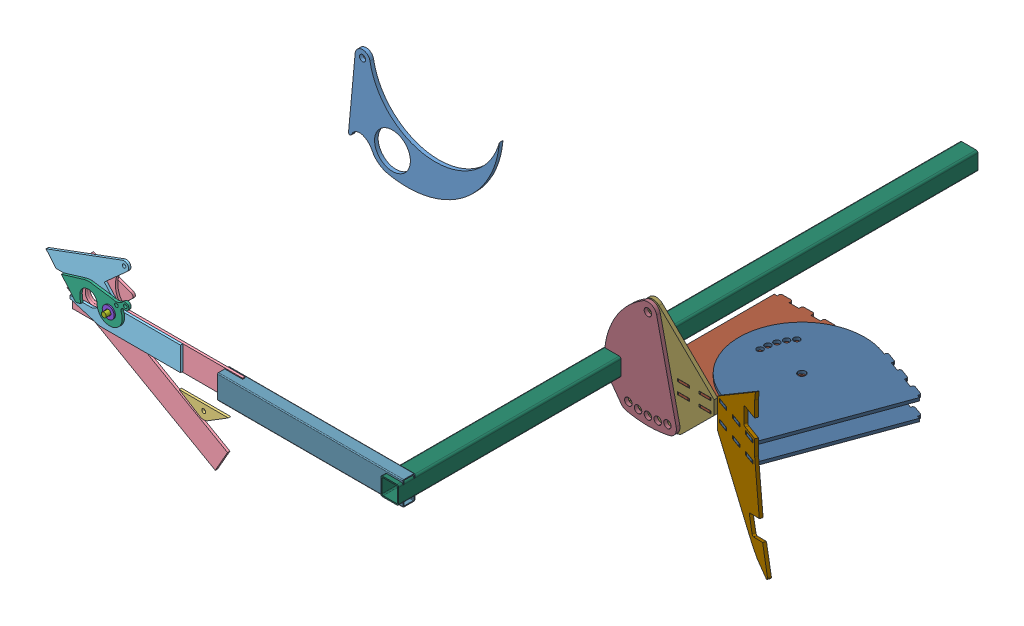
SolidWorks assembly Механизм подъема, configuration 00. Lengths in mm.
Overall size (2305.02 393.93 1176.2).
125 component instances, 32 part files, 102 mates.
Components (placement in the parent):
- Вилка-1: Вилка [--] at (-100 153.8415 0) size (225.09 67 8) (hidden)
- Собачка-1: Собачка [--] at (-64.5 153.8415 -8) size (115.18 50.5 4) (hidden)
- ТП.016.03.05.01 - Ложемент бок (4мм)-1: ТП.016.03.05.01 - Ложемент бок (4мм) [--] at (-100 153.8415 -12) size (285 93.38 4) (hidden)
- ТП.016.03.05.02 - Ложемент низ (4мм)-1: ТП.016.03.05.02 - Ложемент низ (4мм) [--] at (150 118.8415 -16) size (285 4 44) (hidden)
- ТП.016.03.06.01 - Труба связка-1: ТП.016.03.06.01 - Труба связка [--] at (-100 114.8415 28) size (21.3 21.3 971.2) (hidden)
- Модель подъема-1: Модель подъема [--] at (-100 178.8415 -441.6) size (479.74 429.14 0) (hidden)
- ТП.016.03.01.01 - Зуб подъемника (6мм)-1: ТП.016.03.01.01 - Зуб подъемника (6мм) [--] at (-45 169.6674 -441.6) x (0.869959 0.493123 0) z (0 0 1) size (274.94 199.54 6)
- Подшипник ГОСТ 8338-75 -2: Подшипник ГОСТ 8338-75  [Подшипник 205 ГОСТ 8338-75] at (-45 169.6674 -449.1) x (0 0 1) z (-0.017314 -0.99985 0) size (15 52 52) (hidden)
- ТП.016.03.01.02 - Ступица подъема-1: ТП.016.03.01.02 - Ступица подъема [--] at (-45 169.6674 -461.6) x (-1 0 0) z (0 0 -1) size (60 60 40) (hidden)
- ТП.016.03.02 - Ось подъема-1: ТП.016.03.02 - Ось подъема [--] at (-45 169.6674 -461.6) x (-1 0 0) z (0 0 -1) size (25 25 86) (hidden)
- ТП.016.03.03 - Стакан оси подъема-1: ТП.016.03.03 - Стакан оси подъема [--] at (-45 169.6674 -441.6) size (40 40 28) (hidden)
- ТП.016.03.03 - Стакан оси подъема-2: ТП.016.03.03 - Стакан оси подъема [--] at (-45 169.6674 -481.6) x (-1 0 0) z (0 0 -1) size (40 40 28) (hidden)
- ТП.016.03.01.01 - Зуб подъемника (6мм)-2: ТП.016.03.01.01 - Зуб подъемника (6мм) [--] at (-45 169.6674 -475.6) x (0.869959 0.493123 0) z (0 0 1) size (274.94 199.54 6) (hidden)
- Подшипник ГОСТ 8338-75 -3: Подшипник ГОСТ 8338-75  [Подшипник 205 ГОСТ 8338-75] at (-45 169.6674 -474.1) x (0 0 -1) z (0.017314 0.99985 0) size (15 52 52) (hidden)
- ТП.016.03.05.03 - Хомут связки (4мм)-1: ТП.016.03.05.03 - Хомут связки (4мм) [--] at (150 114.8415 -16) size (82.5 38.3 4)
- ТП.016.03.05.04 - Шайба связки (4мм)-1: ТП.016.03.05.04 - Шайба связки (4мм) [--] at (150 114.8415 28) size (82.5 23.3 4)
- ТП.016.03.05.01(01) - Ложемент бок (4мм)-1: ТП.016.03.05.01(01) - Ложемент бок (4мм) [--] at (-100 153.8415 4) size (285 93.13 4)
- ТП.016.03.05.01(01) - Ложемент бок (4мм)-2: ТП.016.03.05.01(01) - Ложемент бок (4мм) [--] at (-100 153.8415 0) x (0.869683 -0.49361 0) z (0 0 1) size (285 93.13 4)
- ТП.016.10.01.01.02.02.01 - Вилка навески (Ст3 S4мм)-1: ТП.016.10.01.01.02.02.01 - Вилка навески (Ст3 S4мм) [ЛАЗЕР] at (-100 153.8415 4) size (225.09 114.93 4)
- ТП.016.10.03.01 - Собачка навески (Ст3 S-4мм)-1: ТП.016.10.03.01 - Собачка навески (Ст3 S-4мм) [На лазер] at (-64.5 153.8415 8) size (112.78 47.58 4)
- ТП.016.10.01.01.02.02.02 - Ось вилки навески-1: ТП.016.10.01.01.02.02.02 - Ось вилки навески [--] at (-64.5 153.8415 4) size (12 12 18)
- ТП.016.10.02 - Втулка собачки навески-1: ТП.016.10.02 - Втулка собачки навески [--] at (-64.5 153.8415 12) size (20 20 6.5)
- ТП.016.11.02.00 - Отвал в сборе-1: ТП.016.11.02.00 - Отвал в сборе [00] at (826.1753 189.0389 -461.6) size (277.03 437.97 1410) (hidden)
  - ТП.016.11.02.01 - Полотно отвала (Ст3 S-2мм)-1: ТП.016.11.02.01 - Полотно отвала (Ст3 S-2мм) [--] at origin size (68.17 399.04 1400)
  - ТП.016.11.02.02 - Продольная труба-1: ТП.016.11.02.02 - Продольная труба [--] at origin size (30 30 1400)
  - ТП.016.11.02.02 - Продольная труба-2: ТП.016.11.02.02 - Продольная труба [--] at (-7.8024 -145.4172 0) x (-0.951057 -0.309017 0) z (0 0 1) size (30 30 1400)
  - ТП.016.11.02.03 - Ребро жесткости отвала (Ст3 S-2мм)-1: ТП.016.11.02.03 - Ребро жесткости отвала (Ст3 S-2мм) [--] at (0 0 675) size (117.05 393.58 2)
  - ТП.016.11.02.03 - Ребро жесткости отвала (Ст3 S-2мм)-2: ТП.016.11.02.03 - Ребро жесткости отвала (Ст3 S-2мм) [--] at (0 0 373) size (117.05 393.58 2)
  - ТП.016.11.02.03 - Ребро жесткости отвала (Ст3 S-2мм)-3: ТП.016.11.02.03 - Ребро жесткости отвала (Ст3 S-2мм) [--] at (0 0 -371) size (117.05 393.58 2)
  - ТП.016.11.02.03 - Ребро жесткости отвала (Ст3 S-2мм)-4: ТП.016.11.02.03 - Ребро жесткости отвала (Ст3 S-2мм) [--] at (0 0 -673) size (117.05 393.58 2)
  - ТП.016.11.02.04.00 - Кронштейн силовой-1: ТП.016.11.02.04.00 - Кронштейн силовой [00] at (-102.2517 -49.6474 0) size (244.94 251.23 220)
    - ТП.016.11.02.04.01 - Цапфа отвала (Ст3 S-5мм)-1: ТП.016.11.02.04.01 - Цапфа отвала (Ст3 S-5мм) [--] at origin size (208.66 5 220)
    - ТП.016.11.02.04.02 - Ребро силовое (Ст3 S-5мм)-1: ТП.016.11.02.04.02 - Ребро силовое (Ст3 S-5мм) [--] at (105.2 0.2 105) size (139.74 251.23 5)
    - ТП.016.11.02.04.02 - Ребро силовое (Ст3 S-5мм)-2: ТП.016.11.02.04.02 - Ребро силовое (Ст3 S-5мм) [--] at (105.2 0.2 -110) size (139.74 251.23 5)
    - ТП.016.11.02.04.01 - Цапфа отвала (Ст3 S-5мм)-2: ТП.016.11.02.04.01 - Цапфа отвала (Ст3 S-5мм) [--] at (0 25.4 0) x (1 0 0) z (0 0 -1) size (208.66 5 220)
  - ТП.016.11.02.05 - Юбка-1: ТП.016.11.02.05 - Юбка [--] at (37.9014 -187.7385 0) x (0.309017 -0.951057 0) z (0 0 1) size (85 8 1410)
  - Болты с шестигранной головкой кт.В (ГОСТ 7798-70)-1: Болты с шестигранной головкой кт.В (ГОСТ 7798-70) [Болт М6-6gx20(S10) ГОСТ 7798-77] at (42.4178 -175.75 690) x (-0.951057 -0.309017 0) z (-0.032305 0.099423 -0.994521) size (24 10.9 10)
  - Шайбы (ГОСТ 11371-78)-1: Шайбы (ГОСТ 11371-78) [Шайба 6 ГОСТ 11371-78] at (32.1464 -179.0874 690) x (0.951057 0.309017 0) z (0.304733 -0.937871 -0.165941) size (1.6 12 12)
  - Гайка (ГОСТ ISO 4032-2014)-1: Гайка (ГОСТ ISO 4032-2014) [Гайка М6 (ГОСТ ISO 4032)] at (28.9128 -180.1381 690) x (0.080366 -0.247341 0.96559) z (0.951057 0.309017 0) size (10 11.05 5.2)
  - Гайка (ГОСТ ISO 4032-2014)-2: Гайка (ГОСТ ISO 4032-2014) [Гайка М6 (ГОСТ ISO 4032)] at (28.9128 -180.1381 552) x (0.14073 -0.433124 0.89028) z (0.951057 0.309017 0) size (10 11.05 5.2)
  - Болты с шестигранной головкой кт.В (ГОСТ 7798-70)-2: Болты с шестигранной головкой кт.В (ГОСТ 7798-70) [Болт М6-6gx20(S10) ГОСТ 7798-77] at (42.4178 -175.75 552) x (-0.951057 -0.309017 0) z (-0.095584 0.294177 -0.950959) size (24 10.9 10)
  - Шайбы (ГОСТ 11371-78)-2: Шайбы (ГОСТ 11371-78) [Шайба 6 ГОСТ 11371-78] at (32.1464 -179.0874 552) x (0.951057 0.309017 0) z (0.287378 -0.884458 -0.367626) size (1.6 12 12)
  - Гайка (ГОСТ ISO 4032-2014)-3: Гайка (ГОСТ ISO 4032-2014) [Гайка М6 (ГОСТ ISO 4032)] at (28.9128 -180.1381 414) x (0.189473 -0.583138 0.789968) z (0.951057 0.309017 0) size (10 11.05 5.2)
  - Болты с шестигранной головкой кт.В (ГОСТ 7798-70)-3: Болты с шестигранной головкой кт.В (ГОСТ 7798-70) [Болт М6-6gx20(S10) ГОСТ 7798-77] at (42.4178 -175.75 414) x (-0.951057 -0.309017 0) z (-0.148605 0.45736 -0.876777) size (24 10.9 10)
  - Шайбы (ГОСТ 11371-78)-3: Шайбы (ГОСТ 11371-78) [Шайба 6 ГОСТ 11371-78] at (32.1464 -179.0874 414) x (0.951057 0.309017 0) z (0.261214 -0.803934 -0.534282) size (1.6 12 12)
  - Гайка (ГОСТ ISO 4032-2014)-4: Гайка (ГОСТ ISO 4032-2014) [Гайка М6 (ГОСТ ISO 4032)] at (28.9128 -180.1381 276) x (0.225997 -0.695549 0.68201) z (0.951057 0.309017 0) size (10 11.05 5.2)
  - Болты с шестигранной головкой кт.В (ГОСТ 7798-70)-4: Болты с шестигранной головкой кт.В (ГОСТ 7798-70) [Болт М6-6gx20(S10) ГОСТ 7798-77] at (42.4178 -175.75 276) x (-0.951057 -0.309017 0) z (-0.189933 0.584555 -0.78881) size (24 10.9 10)
  - Шайбы (ГОСТ 11371-78)-4: Шайбы (ГОСТ 11371-78) [Шайба 6 ГОСТ 11371-78] at (32.1464 -179.0874 276) x (0.951057 0.309017 0) z (0.231523 -0.712554 -0.662318) size (1.6 12 12)
  - Гайка (ГОСТ ISO 4032-2014)-5: Гайка (ГОСТ ISO 4032-2014) [Гайка М6 (ГОСТ ISO 4032)] at (28.9128 -180.1381 138) x (0.250965 -0.77239 0.583464) z (0.951057 0.309017 0) size (10 11.05 5.2)
  - Болты с шестигранной головкой кт.В (ГОСТ 7798-70)-5: Болты с шестигранной головкой кт.В (ГОСТ 7798-70) [Болт М6-6gx20(S10) ГОСТ 7798-77] at (42.4178 -175.75 138) x (-0.951057 -0.309017 0) z (-0.219391 0.675215 -0.704239) size (24 10.9 10)
  - Шайбы (ГОСТ 11371-78)-5: Шайбы (ГОСТ 11371-78) [Шайба 6 ГОСТ 11371-78] at (32.1464 -179.0874 138) x (0.951057 0.309017 0) z (0.203614 -0.626661 -0.752222) size (1.6 12 12)
  - Гайка (ГОСТ ISO 4032-2014)-6: Гайка (ГОСТ ISO 4032-2014) [Гайка М6 (ГОСТ ISO 4032)] at (28.9128 -180.1381 0) x (0.265821 -0.818113 0.509932) z (0.951057 0.309017 0) size (10 11.05 5.2)
  - Болты с шестигранной головкой кт.В (ГОСТ 7798-70)-6: Болты с шестигранной головкой кт.В (ГОСТ 7798-70) [Болт М6-6gx20(S10) ГОСТ 7798-77] at (42.4178 -175.75 0) x (-0.951057 -0.309017 0) z (-0.237644 0.731394 -0.639209) size (24 10.9 10)
  - Шайбы (ГОСТ 11371-78)-6: Шайбы (ГОСТ 11371-78) [Шайба 6 ГОСТ 11371-78] at (32.1464 -179.0874 0) x (0.951057 0.309017 0) z (0.182427 -0.561452 -0.80715) size (1.6 12 12)
  - Гайка (ГОСТ ISO 4032-2014)-7: Гайка (ГОСТ ISO 4032-2014) [Гайка М6 (ГОСТ ISO 4032)] at (28.9128 -180.1381 -138) x (0.272004 -0.837142 0.474559) z (0.951057 0.309017 0) size (10 11.05 5.2)
  - Болты с шестигранной головкой кт.В (ГОСТ 7798-70)-7: Болты с шестигранной головкой кт.В (ГОСТ 7798-70) [Болт М6-6gx20(S10) ГОСТ 7798-77] at (42.4178 -175.75 -138) x (-0.951057 -0.309017 0) z (-0.245474 0.755491 -0.607434) size (24 10.9 10)
  - Шайбы (ГОСТ 11371-78)-7: Шайбы (ГОСТ 11371-78) [Шайба 6 ГОСТ 11371-78] at (32.1464 -179.0874 -138) x (0.951057 0.309017 0) z (0.172142 -0.529798 -0.830471) size (1.6 12 12)
  - Гайка (ГОСТ ISO 4032-2014)-8: Гайка (ГОСТ ISO 4032-2014) [Гайка М6 (ГОСТ ISO 4032)] at (28.9128 -180.1381 -276) x (0.26996 -0.830852 0.486627) z (0.951057 0.309017 0) size (10 11.05 5.2)
  - Болты с шестигранной головкой кт.В (ГОСТ 7798-70)-8: Болты с шестигранной головкой кт.В (ГОСТ 7798-70) [Болт М6-6gx20(S10) ГОСТ 7798-77] at (42.4178 -175.75 -276) x (-0.951057 -0.309017 0) z (-0.242868 0.74747 -0.618307) size (24 10.9 10)
  - Шайбы (ГОСТ 11371-78)-8: Шайбы (ГОСТ 11371-78) [Шайба 6 ГОСТ 11371-78] at (32.1464 -179.0874 -276) x (0.951057 0.309017 0) z (0.175657 -0.540616 -0.822726) size (1.6 12 12)
  - Гайка (ГОСТ ISO 4032-2014)-9: Гайка (ГОСТ ISO 4032-2014) [Гайка М6 (ГОСТ ISO 4032)] at (28.9128 -180.1381 -414) x (0.258386 -0.79523 0.548494) z (0.951057 0.309017 0) size (10 11.05 5.2)
  - Болты с шестигранной головкой кт.В (ГОСТ 7798-70)-9: Болты с шестигранной головкой кт.В (ГОСТ 7798-70) [Болт М6-6gx20(S10) ГОСТ 7798-77] at (42.4178 -175.75 -414) x (-0.951057 -0.309017 0) z (-0.228423 0.703014 -0.673493) size (24 10.9 10)
  - Шайбы (ГОСТ 11371-78)-9: Шайбы (ГОСТ 11371-78) [Шайба 6 ГОСТ 11371-78] at (32.1464 -179.0874 -414) x (0.951057 0.309017 0) z (0.193572 -0.595754 -0.779491) size (1.6 12 12)
  - Гайка (ГОСТ ISO 4032-2014)-10: Гайка (ГОСТ ISO 4032-2014) [Гайка М6 (ГОСТ ISO 4032)] at (28.9128 -180.1381 -552) x (0.234692 -0.722307 0.650532) z (0.951057 0.309017 0) size (10 11.05 5.2)
  - Болты с шестигранной головкой кт.В (ГОСТ 7798-70)-10: Болты с шестигранной головкой кт.В (ГОСТ 7798-70) [Болт М6-6gx20(S10) ГОСТ 7798-77] at (42.4178 -175.75 -552) x (-0.951057 -0.309017 0) z (-0.200053 0.6157 -0.762163) size (24 10.9 10)
  - Шайбы (ГОСТ 11371-78)-10: Шайбы (ГОСТ 11371-78) [Шайба 6 ГОСТ 11371-78] at (32.1464 -179.0874 -552) x (0.951057 0.309017 0) z (0.222677 -0.685331 -0.693352) size (1.6 12 12)
  - Гайка (ГОСТ ISO 4032-2014)-11: Гайка (ГОСТ ISO 4032-2014) [Гайка М6 (ГОСТ ISO 4032)] at (28.9128 -180.1381 -690) x (0.197744 -0.608594 0.768447) z (0.951057 0.309017 0) size (10 11.05 5.2)
  - Болты с шестигранной головкой кт.В (ГОСТ 7798-70)-11: Болты с шестигранной головкой кт.В (ГОСТ 7798-70) [Болт М6-6gx20(S10) ГОСТ 7798-77] at (42.4178 -175.75 -690) x (-0.951057 -0.309017 0) z (-0.157821 0.485724 -0.859747) size (24 10.9 10)
  - Шайбы (ГОСТ 11371-78)-11: Шайбы (ГОСТ 11371-78) [Шайба 6 ГОСТ 11371-78] at (32.1464 -179.0874 -690) x (0.951057 0.309017 0) z (0.25539 -0.786011 -0.562994) size (1.6 12 12)
- ТП.016.11.02.00 - Отвал в сборе-2: ТП.016.11.02.00 - Отвал в сборе [00] at (715.8804 189.0389 -426.6963) x (0.939693 0 0.34202) z (-0.34202 0 0.939693) size (277.03 437.97 1410) (hidden)
  - ТП.016.11.02.01 - Полотно отвала (Ст3 S-2мм)-1: ТП.016.11.02.01 - Полотно отвала (Ст3 S-2мм) [--] at origin size (68.17 399.04 1400)
  - ТП.016.11.02.02 - Продольная труба-1: ТП.016.11.02.02 - Продольная труба [--] at origin size (30 30 1400)
  - ТП.016.11.02.02 - Продольная труба-2: ТП.016.11.02.02 - Продольная труба [--] at (-7.8024 -145.4172 0) x (-0.951057 -0.309017 0) z (0 0 1) size (30 30 1400)
  - ТП.016.11.02.03 - Ребро жесткости отвала (Ст3 S-2мм)-1: ТП.016.11.02.03 - Ребро жесткости отвала (Ст3 S-2мм) [--] at (0 0 675) size (117.05 393.58 2)
  - ТП.016.11.02.03 - Ребро жесткости отвала (Ст3 S-2мм)-2: ТП.016.11.02.03 - Ребро жесткости отвала (Ст3 S-2мм) [--] at (0 0 373) size (117.05 393.58 2)
  - ТП.016.11.02.03 - Ребро жесткости отвала (Ст3 S-2мм)-3: ТП.016.11.02.03 - Ребро жесткости отвала (Ст3 S-2мм) [--] at (0 0 -371) size (117.05 393.58 2)
  - ТП.016.11.02.03 - Ребро жесткости отвала (Ст3 S-2мм)-4: ТП.016.11.02.03 - Ребро жесткости отвала (Ст3 S-2мм) [--] at (0 0 -673) size (117.05 393.58 2)
  - ТП.016.11.02.04.00 - Кронштейн силовой-1: ТП.016.11.02.04.00 - Кронштейн силовой [00] at (-102.2517 -49.6474 0) size (244.94 251.23 220)
    - ТП.016.11.02.04.01 - Цапфа отвала (Ст3 S-5мм)-1: ТП.016.11.02.04.01 - Цапфа отвала (Ст3 S-5мм) [--] at origin size (208.66 5 220)
    - ТП.016.11.02.04.02 - Ребро силовое (Ст3 S-5мм)-1: ТП.016.11.02.04.02 - Ребро силовое (Ст3 S-5мм) [--] at (105.2 0.2 105) size (139.74 251.23 5)
    - ТП.016.11.02.04.02 - Ребро силовое (Ст3 S-5мм)-2: ТП.016.11.02.04.02 - Ребро силовое (Ст3 S-5мм) [--] at (105.2 0.2 -110) size (139.74 251.23 5)
    - ТП.016.11.02.04.01 - Цапфа отвала (Ст3 S-5мм)-2: ТП.016.11.02.04.01 - Цапфа отвала (Ст3 S-5мм) [--] at (0 25.4 0) x (1 0 0) z (0 0 -1) size (208.66 5 220)
  - ТП.016.11.02.05 - Юбка-1: ТП.016.11.02.05 - Юбка [--] at (37.9014 -187.7385 0) x (0.309017 -0.951057 0) z (0 0 1) size (85 8 1410)
  - Болты с шестигранной головкой кт.В (ГОСТ 7798-70)-1: Болты с шестигранной головкой кт.В (ГОСТ 7798-70) [Болт М6-6gx20(S10) ГОСТ 7798-77] at (42.4178 -175.75 690) x (-0.951057 -0.309017 0) z (-0.032305 0.099423 -0.994521) size (24 10.9 10)
  - Шайбы (ГОСТ 11371-78)-1: Шайбы (ГОСТ 11371-78) [Шайба 6 ГОСТ 11371-78] at (32.1464 -179.0874 690) x (0.951057 0.309017 0) z (0.304733 -0.937871 -0.165941) size (1.6 12 12)
  - Гайка (ГОСТ ISO 4032-2014)-1: Гайка (ГОСТ ISO 4032-2014) [Гайка М6 (ГОСТ ISO 4032)] at (28.9128 -180.1381 690) x (0.080366 -0.247341 0.96559) z (0.951057 0.309017 0) size (10 11.05 5.2)
  - Гайка (ГОСТ ISO 4032-2014)-2: Гайка (ГОСТ ISO 4032-2014) [Гайка М6 (ГОСТ ISO 4032)] at (28.9128 -180.1381 552) x (0.14073 -0.433124 0.89028) z (0.951057 0.309017 0) size (10 11.05 5.2)
  - Болты с шестигранной головкой кт.В (ГОСТ 7798-70)-2: Болты с шестигранной головкой кт.В (ГОСТ 7798-70) [Болт М6-6gx20(S10) ГОСТ 7798-77] at (42.4178 -175.75 552) x (-0.951057 -0.309017 0) z (-0.095584 0.294177 -0.950959) size (24 10.9 10)
  - Шайбы (ГОСТ 11371-78)-2: Шайбы (ГОСТ 11371-78) [Шайба 6 ГОСТ 11371-78] at (32.1464 -179.0874 552) x (0.951057 0.309017 0) z (0.287378 -0.884458 -0.367626) size (1.6 12 12)
  - Гайка (ГОСТ ISO 4032-2014)-3: Гайка (ГОСТ ISO 4032-2014) [Гайка М6 (ГОСТ ISO 4032)] at (28.9128 -180.1381 414) x (0.189473 -0.583138 0.789968) z (0.951057 0.309017 0) size (10 11.05 5.2)
  - Болты с шестигранной головкой кт.В (ГОСТ 7798-70)-3: Болты с шестигранной головкой кт.В (ГОСТ 7798-70) [Болт М6-6gx20(S10) ГОСТ 7798-77] at (42.4178 -175.75 414) x (-0.951057 -0.309017 0) z (-0.148605 0.45736 -0.876777) size (24 10.9 10)
  - Шайбы (ГОСТ 11371-78)-3: Шайбы (ГОСТ 11371-78) [Шайба 6 ГОСТ 11371-78] at (32.1464 -179.0874 414) x (0.951057 0.309017 0) z (0.261214 -0.803934 -0.534282) size (1.6 12 12)
  - Гайка (ГОСТ ISO 4032-2014)-4: Гайка (ГОСТ ISO 4032-2014) [Гайка М6 (ГОСТ ISO 4032)] at (28.9128 -180.1381 276) x (0.225997 -0.695549 0.68201) z (0.951057 0.309017 0) size (10 11.05 5.2)
  - Болты с шестигранной головкой кт.В (ГОСТ 7798-70)-4: Болты с шестигранной головкой кт.В (ГОСТ 7798-70) [Болт М6-6gx20(S10) ГОСТ 7798-77] at (42.4178 -175.75 276) x (-0.951057 -0.309017 0) z (-0.189933 0.584555 -0.78881) size (24 10.9 10)
  - Шайбы (ГОСТ 11371-78)-4: Шайбы (ГОСТ 11371-78) [Шайба 6 ГОСТ 11371-78] at (32.1464 -179.0874 276) x (0.951057 0.309017 0) z (0.231523 -0.712554 -0.662318) size (1.6 12 12)
  - Гайка (ГОСТ ISO 4032-2014)-5: Гайка (ГОСТ ISO 4032-2014) [Гайка М6 (ГОСТ ISO 4032)] at (28.9128 -180.1381 138) x (0.250965 -0.77239 0.583464) z (0.951057 0.309017 0) size (10 11.05 5.2)
  - Болты с шестигранной головкой кт.В (ГОСТ 7798-70)-5: Болты с шестигранной головкой кт.В (ГОСТ 7798-70) [Болт М6-6gx20(S10) ГОСТ 7798-77] at (42.4178 -175.75 138) x (-0.951057 -0.309017 0) z (-0.219391 0.675215 -0.704239) size (24 10.9 10)
  - Шайбы (ГОСТ 11371-78)-5: Шайбы (ГОСТ 11371-78) [Шайба 6 ГОСТ 11371-78] at (32.1464 -179.0874 138) x (0.951057 0.309017 0) z (0.203614 -0.626661 -0.752222) size (1.6 12 12)
  - Гайка (ГОСТ ISO 4032-2014)-6: Гайка (ГОСТ ISO 4032-2014) [Гайка М6 (ГОСТ ISO 4032)] at (28.9128 -180.1381 0) x (0.265821 -0.818113 0.509932) z (0.951057 0.309017 0) size (10 11.05 5.2)
  - Болты с шестигранной головкой кт.В (ГОСТ 7798-70)-6: Болты с шестигранной головкой кт.В (ГОСТ 7798-70) [Болт М6-6gx20(S10) ГОСТ 7798-77] at (42.4178 -175.75 0) x (-0.951057 -0.309017 0) z (-0.237644 0.731394 -0.639209) size (24 10.9 10)
  - Шайбы (ГОСТ 11371-78)-6: Шайбы (ГОСТ 11371-78) [Шайба 6 ГОСТ 11371-78] at (32.1464 -179.0874 0) x (0.951057 0.309017 0) z (0.182427 -0.561452 -0.80715) size (1.6 12 12)
  - Гайка (ГОСТ ISO 4032-2014)-7: Гайка (ГОСТ ISO 4032-2014) [Гайка М6 (ГОСТ ISO 4032)] at (28.9128 -180.1381 -138) x (0.272004 -0.837142 0.474559) z (0.951057 0.309017 0) size (10 11.05 5.2)
  - Болты с шестигранной головкой кт.В (ГОСТ 7798-70)-7: Болты с шестигранной головкой кт.В (ГОСТ 7798-70) [Болт М6-6gx20(S10) ГОСТ 7798-77] at (42.4178 -175.75 -138) x (-0.951057 -0.309017 0) z (-0.245474 0.755491 -0.607434) size (24 10.9 10)
  - Шайбы (ГОСТ 11371-78)-7: Шайбы (ГОСТ 11371-78) [Шайба 6 ГОСТ 11371-78] at (32.1464 -179.0874 -138) x (0.951057 0.309017 0) z (0.172142 -0.529798 -0.830471) size (1.6 12 12)
  - Гайка (ГОСТ ISO 4032-2014)-8: Гайка (ГОСТ ISO 4032-2014) [Гайка М6 (ГОСТ ISO 4032)] at (28.9128 -180.1381 -276) x (0.26996 -0.830852 0.486627) z (0.951057 0.309017 0) size (10 11.05 5.2)
  - Болты с шестигранной головкой кт.В (ГОСТ 7798-70)-8: Болты с шестигранной головкой кт.В (ГОСТ 7798-70) [Болт М6-6gx20(S10) ГОСТ 7798-77] at (42.4178 -175.75 -276) x (-0.951057 -0.309017 0) z (-0.242868 0.74747 -0.618307) size (24 10.9 10)
  - Шайбы (ГОСТ 11371-78)-8: Шайбы (ГОСТ 11371-78) [Шайба 6 ГОСТ 11371-78] at (32.1464 -179.0874 -276) x (0.951057 0.309017 0) z (0.175657 -0.540616 -0.822726) size (1.6 12 12)
  - Гайка (ГОСТ ISO 4032-2014)-9: Гайка (ГОСТ ISO 4032-2014) [Гайка М6 (ГОСТ ISO 4032)] at (28.9128 -180.1381 -414) x (0.258386 -0.79523 0.548494) z (0.951057 0.309017 0) size (10 11.05 5.2)
  - Болты с шестигранной головкой кт.В (ГОСТ 7798-70)-9: Болты с шестигранной головкой кт.В (ГОСТ 7798-70) [Болт М6-6gx20(S10) ГОСТ 7798-77] at (42.4178 -175.75 -414) x (-0.951057 -0.309017 0) z (-0.228423 0.703014 -0.673493) size (24 10.9 10)
  - Шайбы (ГОСТ 11371-78)-9: Шайбы (ГОСТ 11371-78) [Шайба 6 ГОСТ 11371-78] at (32.1464 -179.0874 -414) x (0.951057 0.309017 0) z (0.193572 -0.595754 -0.779491) size (1.6 12 12)
  - Гайка (ГОСТ ISO 4032-2014)-10: Гайка (ГОСТ ISO 4032-2014) [Гайка М6 (ГОСТ ISO 4032)] at (28.9128 -180.1381 -552) x (0.234692 -0.722307 0.650532) z (0.951057 0.309017 0) size (10 11.05 5.2)
  - Болты с шестигранной головкой кт.В (ГОСТ 7798-70)-10: Болты с шестигранной головкой кт.В (ГОСТ 7798-70) [Болт М6-6gx20(S10) ГОСТ 7798-77] at (42.4178 -175.75 -552) x (-0.951057 -0.309017 0) z (-0.200053 0.6157 -0.762163) size (24 10.9 10)
  - Шайбы (ГОСТ 11371-78)-10: Шайбы (ГОСТ 11371-78) [Шайба 6 ГОСТ 11371-78] at (32.1464 -179.0874 -552) x (0.951057 0.309017 0) z (0.222677 -0.685331 -0.693352) size (1.6 12 12)
  - Гайка (ГОСТ ISO 4032-2014)-11: Гайка (ГОСТ ISO 4032-2014) [Гайка М6 (ГОСТ ISO 4032)] at (28.9128 -180.1381 -690) x (0.197744 -0.608594 0.768447) z (0.951057 0.309017 0) size (10 11.05 5.2)
  - Болты с шестигранной головкой кт.В (ГОСТ 7798-70)-11: Болты с шестигранной головкой кт.В (ГОСТ 7798-70) [Болт М6-6gx20(S10) ГОСТ 7798-77] at (42.4178 -175.75 -690) x (-0.951057 -0.309017 0) z (-0.157821 0.485724 -0.859747) size (24 10.9 10)
  - Шайбы (ГОСТ 11371-78)-11: Шайбы (ГОСТ 11371-78) [Шайба 6 ГОСТ 11371-78] at (32.1464 -179.0874 -690) x (0.951057 0.309017 0) z (0.25539 -0.786011 -0.562994) size (1.6 12 12)
- ТП.016.11.02.04.02 - Ребро силовое (Ст3 S-5мм)-1: ТП.016.11.02.04.02 - Ребро силовое (Ст3 S-5мм) [--] at (682.7388 139.5915 -327.0202) x (0.939693 0 0.34202) z (-0.34202 0 0.939693) size (139.74 251.23 5)
- ТП.016.11.02.04.01 - Цапфа отвала (Ст3 S-5мм)-1: ТП.016.11.02.04.01 - Цапфа отвала (Ст3 S-5мм) [--] at (619.9831 139.5915 -461.6) x (0.939693 0 0.34202) z (-0.34202 0 0.939693) size (208.66 5 220)
- ТП.016.11.01.01.01 - Цапфа навески (Ст3 S-4мм)-1: ТП.016.11.01.01.01 - Цапфа навески (Ст3 S-4мм) [--] at (619.9831 139.5915 -461.6) size (200 4 209.34)
- ТП.016.11.01.02 - Кронштейн навески (Ст3 S-6мм)-1: ТП.016.11.01.02 - Кронштейн навески (Ст3 S-6мм) [--] at (577.703 139.5915 -362.9323) x (-1 0 0) z (0 0 1) size (156.54 180 6)
- ТП.016.11.01.01.01 - Цапфа навески (Ст3 S-4мм)-2: ТП.016.11.01.01.01 - Цапфа навески (Ст3 S-4мм) [--] at (619.9831 158.5915 -461.6) size (200 4 209.34)
- ТП.016.11.02.04.01 - Цапфа отвала (Ст3 S-5мм)-2: ТП.016.11.02.04.01 - Цапфа отвала (Ст3 S-5мм) [--] at (619.9831 169.5915 -461.6) x (0.939693 0 0.34202) z (-0.34202 0 0.939693) size (208.66 5 220)
- ТП.016.10.01.02 - Кронштейн рампы (Ст3 S-6мм)-1: ТП.016.10.01.02 - Кронштейн рампы (Ст3 S-6мм) [--] at (415 139.5915 -354.9323) size (119.68 179.72 6)
- ТП.016.10.01.01.02.01 - Боковина рампы-1: ТП.016.10.01.01.02.01 - Боковина рампы [--] at (400 118.8415 -4) x (0 0 -1) z (1 0 0) size (20 40 310)
- ТП.016.10.01.01.01 - Поперечина рампы-1: ТП.016.10.01.01.01 - Поперечина рампы [--] at (415 139.5915 -461.6) size (30 30 969.2)
Mates (geometry in assembly coordinates):
- Совпадение1: coincident: plane of Вилка-1 through (-100 153.8415 0) normal (0 0 1); plane of assembly through (0 0 0) normal (0 0 1)
- Совпадение2: coincident: plane of Вилка-1 through (-100 153.8415 0) normal (0 1 0); point of assembly
- Совпадение3: coincident: plane of Вилка-1 through (-100 153.8415 0) normal (1 0 0); point of assembly
- Параллельность1: parallel: plane of Вилка-1 through (-100 153.8415 0) normal (0 1 0); line of assembly
- Совпадение4: coincident: plane of Вилка-1 through (-100 153.8415 -8) normal (0 0 -1); plane of Собачка-1 through (-64.5 153.8415 -8) normal (0 0 1)
- Совпадение5: coincident: point of Вилка-1; plane of Собачка-1 through (-64.5 153.8415 -8) normal (0 1 0)
- Параллельность2: parallel: plane of Вилка-1 through (50 120.3415 -8) normal (0 -1 0); plane of Собачка-1 through (-64.5 153.8415 -8) normal (0 1 0)
- Совпадение6: coincident: plane of Собачка-1 through (-64.5 153.8415 -8) normal (1 0 0); point of assembly
- Совпадение7: coincident: plane of Собачка-1 through (-100 153.8415 -12) normal (0 0 -1); plane of ТП.016.03.05.01 - Ложемент бок (4мм)-1 through (-100 153.8415 -12) normal (0 0 1)
- Совпадение8: coincident: plane of ТП.016.03.05.01 - Ложемент бок (4мм)-1 through (-100 153.8415 -12) normal (0 1 0); point of assembly
- Совпадение9: coincident: plane of ТП.016.03.05.01 - Ложемент бок (4мм)-1 through (-100 153.8415 -12) normal (1 0 0); point of assembly
- Параллельность3: parallel: plane of Вилка-1 through (50 120.3415 -8) normal (0 -1 0); plane of ТП.016.03.05.01 - Ложемент бок (4мм)-1 through (-100 153.8415 -12) normal (0 1 0)
- Совпадение10: coincident: plane of ТП.016.03.05.01 - Ложемент бок (4мм)-1 through (-19.33 190.8761 -16) normal (0 0 -1); plane of ТП.016.03.05.02 - Ложемент низ (4мм)-1 through (150 118.8415 -16) normal (0 0 1)
- Совпадение11: coincident: plane of ТП.016.03.05.01 - Ложемент бок (4мм)-1 through (-100 118.8415 -16) normal (0 -1 0); plane of ТП.016.03.05.02 - Ложемент низ (4мм)-1 through (150 118.8415 -16) normal (0 1 0)
- Совпадение12: coincident: plane of ТП.016.03.05.01 - Ложемент бок (4мм)-1 through (150 118.8415 -16) normal (1 0 0); plane of ТП.016.03.05.02 - Ложемент низ (4мм)-1 through (150 118.8415 -16) normal (1 0 0)
- Совпадение13: coincident: plane of ТП.016.03.05.02 - Ложемент низ (4мм)-1 through (-135 114.8415 28) normal (0 0 1); plane of ТП.016.03.06.01 - Труба связка-1 through (-100 114.8415 28) normal (0 0 1)
- Совпадение14: coincident: plane of ТП.016.03.05.02 - Ложемент низ (4мм)-1 through (150 114.8415 -16) normal (0 -1 0); plane of ТП.016.03.06.01 - Труба связка-1 through (-100 114.8415 28) normal (0 1 0)
- Совпадение15: coincident: plane of ТП.016.03.06.01 - Труба связка-1 through (-100 114.8415 28) normal (1 0 0); point of assembly
- Совпадение16: coincident: plane of ? through (171.6828 47.7635 -200) normal (0 0 1); plane of assembly through (0 0 -200) normal (0 0 1)
- Совпадение17: coincident: plane of Модель подъема-1 through (-100 178.8415 -441.6) normal (0 0 1); plane of assembly through (0 0 -441.6) normal (0 0 1)
- Совпадение18: coincident: plane of Модель подъема-1 through (-100 178.8415 -441.6) normal (0 1 0); line of assembly
- Совпадение19: coincident: plane of Модель подъема-1 through (-100 178.8415 -441.6) normal (1 0 0); point of assembly
- Совпадение20: coincident: plane of ТП.016.03.01.01 - Зуб подъемника (6мм)-1 through (-45 169.6674 -441.6) normal (0 0 1); plane of assembly through (0 0 -441.6) normal (0 0 1)
- Совпадение21: coincident: point of Модель подъема-1; plane of ТП.016.03.01.01 - Зуб подъемника (6мм)-1 through (-45 169.6674 -441.6) normal (-0.493123 0.869959 0)
- Совпадение22: coincident: point of Модель подъема-1; plane of ТП.016.03.01.01 - Зуб подъемника (6мм)-1 through (-45 169.6674 -441.6) normal (-0.493123 0.869959 0)
- Совпадение23: coincident: point of Модель подъема-1; plane of ТП.016.03.01.01 - Зуб подъемника (6мм)-1 through (-45 169.6674 -441.6) normal (0.869959 0.493123 0)
- Совпадение24: coincident: plane of ТП.016.03.01.01 - Зуб подъемника (6мм)-1 through (-20.6077 284.0965 -441.6) normal (0 0 1); plane of Подшипник ГОСТ 8338-75 -2 through (-65.9969 170.031 -441.6) normal (0 0 1)
- Концентричный1: concentric: cylinder of ТП.016.03.01.01 - Зуб подъемника (6мм)-1 through (-45 169.6674 -447.6) axis (0 0 1) radius 30; cylinder of Подшипник ГОСТ 8338-75 -2 through (-45 169.6674 -1449.1) axis (0 0 -1) radius 26
- Совпадение25: coincident: plane of ТП.016.03.01.02 - Ступица подъема-1 through (-45 169.6674 -461.6) normal (0 0 -1); plane of assembly through (0 0 -461.6) normal (0 0 1)
- Совпадение26: coincident: point of Модель подъема-1; plane of ТП.016.03.01.02 - Ступица подъема-1 through (-45 169.6674 -461.6) normal (0 1 0)
- Параллельность4: parallel: plane of ТП.016.03.01.02 - Ступица подъема-1 through (-45 169.6674 -461.6) normal (0 1 0); plane of assembly through (0 0 0) normal (0 1 0)
- Совпадение27: coincident: point of Модель подъема-1; plane of ТП.016.03.01.02 - Ступица подъема-1 through (-45 169.6674 -461.6) normal (-1 0 0)
- Совпадение28: coordinate: point of ТП.016.03.01.02 - Ступица подъема-1; point of ТП.016.03.02 - Ось подъема-1
- Совпадение29: coincident: plane of Подшипник ГОСТ 8338-75 -2 through (-58.9979 169.9098 -441.6) normal (0 0 1); plane of ТП.016.03.03 - Стакан оси подъема-1 through (-45 169.6674 -441.6) normal (0 0 1)
- Совпадение30: coincident: plane of ТП.016.03.02 - Ось подъема-1 through (-45 169.6674 -461.6) normal (0 1 0); plane of ТП.016.03.03 - Стакан оси подъема-1 through (-45 169.6674 -441.6) normal (0 1 0)
- Совпадение31: coincident: plane of ТП.016.03.02 - Ось подъема-1 through (-45 169.6674 -461.6) normal (-1 0 0); plane of ТП.016.03.03 - Стакан оси подъема-1 through (-45 169.6674 -441.6) normal (1 0 0)
- Совпадение32: coincident: plane of ТП.016.03.05.01 - Ложемент бок (4мм)-1 through (-19.33 190.8761 -16) normal (0 0 -1); plane of ТП.016.03.05.03 - Хомут связки (4мм)-1 through (150 114.8415 -16) normal (0 0 1)
- Совпадение33: coincident: plane of ТП.016.03.05.02 - Ложемент низ (4мм)-1 through (150 114.8415 -16) normal (0 -1 0); plane of ТП.016.03.05.03 - Хомут связки (4мм)-1 through (150 114.8415 -16) normal (0 1 0)
- Совпадение34: coincident: plane of ТП.016.03.05.02 - Ложемент низ (4мм)-1 through (150 114.8415 28) normal (1 0 0); plane of ТП.016.03.05.03 - Хомут связки (4мм)-1 through (150 114.8415 -16) normal (1 0 0)
- Совпадение35: coincident: plane of ТП.016.03.05.02 - Ложемент низ (4мм)-1 through (-135 114.8415 28) normal (0 0 1); plane of ТП.016.03.05.04 - Шайба связки (4мм)-1 through (150 114.8415 28) normal (0 0 1)
- Совпадение36: coincident: plane of ТП.016.03.05.03 - Хомут связки (4мм)-1 through (150 114.8415 -16) normal (0 1 0); plane of ТП.016.03.05.04 - Шайба связки (4мм)-1 through (150 114.8415 28) normal (0 1 0)
- Совпадение37: coincident: plane of ТП.016.03.05.03 - Хомут связки (4мм)-1 through (150 114.8415 -16) normal (1 0 0); plane of ТП.016.03.05.04 - Шайба связки (4мм)-1 through (150 114.8415 28) normal (1 0 0)
- Совпадение38: coincident: plane of ? through (-24.6054 189.1519 0) normal (0 0 -1)
- Концентричный2: concentric: cylinder of ? through (-100 153.8415 0) axis (0 0 1) radius 13.5
- Параллельность5: parallel: plane of ? through (-100 118.8415 0) normal (0 -1 0)
- Совпадение39: coincident: plane of ТП.016.03.05.01(01) - Ложемент бок (4мм)-1 through (-24.6054 189.1519 0) normal (0 0 -1); plane of ТП.016.03.05.01(01) - Ложемент бок (4мм)-2 through (-17.001 147.3348 0) normal (0 0 1)
- Параллельность6: parallel: line of ТП.016.03.05.01(01) - Ложемент бок (4мм)-2 through (285 -147.7153 140.679) axis (0 0.869683 -0.49361); line of assembly
- Концентричный3: concentric: cylinder of ТП.016.03.05.01(01) - Ложемент бок (4мм)-1 through (-100 153.8415 0) axis (0 0 1) radius 13.5; cylinder of ТП.016.03.05.01(01) - Ложемент бок (4мм)-2 through (-100 153.8415 -4) axis (0 0 1) radius 13.5
- Совпадение40: coincident: plane of ТП.016.03.05.01(01) - Ложемент бок (4мм)-1 through (-24.6054 189.1519 4) normal (0 0 1); plane of ТП.016.10.01.01.02.02.01 - Вилка навески (Ст3 S4мм)-1 through (-100 153.8415 4) normal (0 0 1)
- Совпадение41: coincident: plane of ? through (-100 153.8415 4) normal (0 1 0)
- Совпадение42: coincident: plane of ? through (-100 153.8415 4) normal (1 0 0)
- Параллельность7: parallel: plane of ТП.016.03.05.01(01) - Ложемент бок (4мм)-1 through (-135 118.8415 0) normal (-1 0 0); plane of ТП.016.10.01.01.02.02.01 - Вилка навески (Ст3 S4мм)-1 through (-100 153.8415 4) normal (1 0 0)
- Совпадение43: coincident: plane of ТП.016.10.01.01.02.02.01 - Вилка навески (Ст3 S4мм)-1 through (-44.5 227.7764 8) normal (0 0 1); plane of ТП.016.10.03.01 - Собачка навески (Ст3 S-4мм)-1 through (-64.5 153.8415 8) normal (0 0 1)
- Совпадение44: coincident: plane of ТП.016.10.03.01 - Собачка навески (Ст3 S-4мм)-1 through (-64.5 153.8415 8) normal (0 1 0); point of assembly
- Совпадение45: coincident: plane of ТП.016.10.03.01 - Собачка навески (Ст3 S-4мм)-1 through (-64.5 153.8415 8) normal (1 0 0); point of assembly
- Параллельность8: parallel: plane of ТП.016.03.05.01(01) - Ложемент бок (4мм)-1 through (-135 118.8415 0) normal (-1 0 0); plane of ТП.016.10.03.01 - Собачка навески (Ст3 S-4мм)-1 through (-64.5 153.8415 8) normal (1 0 0)
- Совпадение46: coincident: plane of ТП.016.03.05.01(01) - Ложемент бок (4мм)-1 through (-24.6054 189.1519 4) normal (0 0 1); plane of ТП.016.10.01.01.02.02.02 - Ось вилки навески-1 through (-64.5 153.8415 4) normal (0 0 1)
- Совпадение48: coincident: plane of ТП.016.10.01.01.02.02.02 - Ось вилки навески-1 through (-64.5 153.8415 4) normal (1 0 0); point of assembly
- Совпадение49: coincident: plane of ТП.016.10.01.01.02.02.02 - Ось вилки навески-1 through (-64.5 153.8415 4) normal (0 1 0); point of assembly
- Параллельность9: parallel: plane of ТП.016.03.05.01(01) - Ложемент бок (4мм)-1 through (-135 118.8415 0) normal (-1 0 0); plane of ТП.016.10.01.01.02.02.02 - Ось вилки навески-1 through (-64.5 153.8415 4) normal (1 0 0)
- Совпадение50: coincident: plane of ТП.016.10.03.01 - Собачка навески (Ст3 S-4мм)-1 through (-100 153.8415 12) normal (0 0 1); plane of ТП.016.10.02 - Втулка собачки навески-1 through (-64.5 153.8415 12) normal (0 0 1)
- Совпадение51: coincident: plane of ТП.016.10.01.01.02.02.02 - Ось вилки навески-1 through (-64.5 153.8415 4) normal (0 1 0); point of assembly
- Совпадение52: coincident: plane of ТП.016.10.02 - Втулка собачки навески-1 through (-64.5 153.8415 12) normal (1 0 0); point of assembly
- Параллельность10: parallel: plane of ТП.016.03.05.01(01) - Ложемент бок (4мм)-1 through (-135 118.8415 0) normal (-1 0 0); plane of ТП.016.10.02 - Втулка собачки навески-1 through (-64.5 153.8415 12) normal (1 0 0)
- Совпадение53: coincident: plane of ТП.016.10.02 - Втулка собачки навески-1 through (-64.5 153.8415 12) normal (0 1 0); point of assembly
- Касательность1: tangent: cylinder of ? through (860.8665 -5 238.4) axis (0 0 -1) radius 5
- Параллельность11: parallel: plane of ? through (826.1753 189.0389 -461.6) normal (0 1 0); plane of assembly through (0 0 0) normal (0 1 0)
- Совпадение54: coincident: plane of ? through (826.1753 189.0389 -461.6) normal (0 0 1)
- Касательность2: tangent: cylinder of ? through (509.0654 -5 242.9537) axis (0.34202 0 -0.939693) radius 5
- Параллельность12: parallel: plane of ? through (715.8804 189.0389 -426.6963) normal (0 1 0); plane of assembly through (0 0 0) normal (0 1 0)
- Совпадение55: coincident: plane of ? through (477.9802 148.0342 231.6396) normal (-0.928123 -0.156434 -0.337809)
- Совпадение56: coincident: plane of ? through (715.8804 189.0389 -426.6963) normal (-0.34202 0 0.939693)
- Совпадение57: coincident: plane of ? through (682.7388 139.5915 -327.0202) normal (-0.34202 0 0.939693)
- Совпадение58: coincident: plane of ? through (682.7388 139.5915 -327.0202) normal (0 1 0)
- Совпадение59: coincident: plane of ? through (682.7388 139.5915 -327.0202) normal (0 1 0)
- Совпадение60: coincident: plane of ? through (682.7388 139.5915 -327.0202) normal (0.939693 0 0.34202)
- Совпадение61: coincident: plane of ТП.016.11.02.04.01 - Цапфа отвала (Ст3 S-5мм)-1 through (619.9831 139.5915 -461.6) normal (0 1 0); circle of assembly
- Совпадение62: coincident: plane of ТП.016.11.02.04.01 - Цапфа отвала (Ст3 S-5мм)-1 through (619.9831 139.5915 -461.6) normal (-0.34202 0 0.939693); line of assembly
- Совпадение63: coincident: plane of ТП.016.11.02.04.01 - Цапфа отвала (Ст3 S-5мм)-1 through (619.9831 139.5915 -461.6) normal (0.939693 0 0.34202); line of assembly
- Совпадение64: coincident: plane of ТП.016.11.02.04.01 - Цапфа отвала (Ст3 S-5мм)-1 through (619.9831 139.5915 -461.6) normal (0 1 0); plane of ТП.016.11.01.01.01 - Цапфа навески (Ст3 S-4мм)-1 through (619.9831 139.5915 -461.6) normal (0 1 0)
- Совпадение65: coincident: plane of ТП.016.11.01.01.01 - Цапфа навески (Ст3 S-4мм)-1 through (619.9831 139.5915 -461.6) normal (0 0 1); line of assembly
- Совпадение66: coincident: plane of ТП.016.11.01.01.01 - Цапфа навески (Ст3 S-4мм)-1 through (619.9831 139.5915 -461.6) normal (1 0 0); point of assembly
- Совпадение67: coincident: plane of ТП.016.11.01.01.01 - Цапфа навески (Ст3 S-4мм)-1 through (577.703 143.5915 -362.9323) normal (0 0 1); plane of ТП.016.11.01.02 - Кронштейн навески (Ст3 S-6мм)-1 through (577.703 139.5915 -362.9323) normal (0 0 1)
- Совпадение68: coincident: plane of ТП.016.11.01.01.01 - Цапфа навески (Ст3 S-4мм)-1 through (549.9831 139.5915 -461.6) normal (0 -1 0); plane of ТП.016.11.01.02 - Кронштейн навески (Ст3 S-6мм)-1 through (577.703 139.5915 -362.9323) normal (0 -1 0)
- Совпадение69: coincident: line of ТП.016.11.01.01.01 - Цапфа навески (Ст3 S-4мм)-1 through (577.703 143.5915 -362.9323) axis (0 -1 0); plane of ТП.016.11.01.02 - Кронштейн навески (Ст3 S-6мм)-1 through (577.703 139.5915 -362.9323) normal (-1 0 0)
- Совпадение70: coincident: plane of ТП.016.11.01.01.01 - Цапфа навески (Ст3 S-4мм)-1 through (474.9831 143.5915 -362.9323) normal (-1 0 0); plane of ТП.016.11.01.01.01 - Цапфа навески (Ст3 S-4мм)-2 through (474.9831 162.5915 -362.9323) normal (-1 0 0)
- Совпадение71: coincident: point of ТП.016.11.01.02 - Кронштейн навески (Ст3 S-6мм)-1; plane of ТП.016.11.01.01.01 - Цапфа навески (Ст3 S-4мм)-2 through (549.9831 162.5915 -461.6) normal (0 1 0)
- Концентричный4: concentric: cylinder of ТП.016.11.01.01.01 - Цапфа навески (Ст3 S-4мм)-1 through (619.9831 143.5915 -461.6) axis (0 -1 0) radius 6.25; cylinder of ТП.016.11.01.01.01 - Цапфа навески (Ст3 S-4мм)-2 through (619.9831 162.5915 -461.6) axis (0 -1 0) radius 6.25
- Совпадение72: coincident: plane of ТП.016.11.02.04.01 - Цапфа отвала (Ст3 S-5мм)-1 through (681.4822 134.5915 -327.4775) normal (0.939693 0 0.34202); plane of ТП.016.11.02.04.01 - Цапфа отвала (Ст3 S-5мм)-2 through (681.4822 164.5915 -327.4775) normal (0.939693 0 0.34202)
- Совпадение73: coincident: plane of ТП.016.11.02.04.01 - Цапфа отвала (Ст3 S-5мм)-1 through (820.8758 185.1361 -271.4215) normal (-0.34202 0 0.939693); plane of ТП.016.11.02.04.01 - Цапфа отвала (Ст3 S-5мм)-2 through (820.8758 215.1361 -271.4215) normal (-0.34202 0 0.939693)
- Расстояние1: distance = 2 mm: plane of ТП.016.11.01.01.01 - Цапфа навески (Ст3 S-4мм)-2 through (549.9831 162.5915 -461.6) normal (0 1 0); plane of ТП.016.11.02.04.01 - Цапфа отвала (Ст3 S-5мм)-2 through (619.9831 164.5915 -461.6) normal (0 -1 0)
- Расстояние2: distance = 2 mm: plane of ТП.016.10.01.02 - Кронштейн рампы (Ст3 S-6мм)-1 through (415 139.5915 -354.9323) normal (0 0 1); plane of ТП.016.11.01.02 - Кронштейн навески (Ст3 S-6мм)-1 through (513.806 97.2026 -356.9323) normal (0 0 1)
- Совпадение74: coincident: plane of ТП.016.10.01.02 - Кронштейн рампы (Ст3 S-6мм)-1 through (415 139.5915 -354.9323) normal (0 1 0); line of assembly
- Совпадение75: coincident: plane of ТП.016.10.01.02 - Кронштейн рампы (Ст3 S-6мм)-1 through (415 139.5915 -354.9323) normal (0 1 0); line of assembly
- Совпадение76: coincident: plane of ТП.016.10.01.02 - Кронштейн рампы (Ст3 S-6мм)-1 through (415 139.5915 -354.9323) normal (1 0 0); point of assembly
- Совпадение77: coincident: plane of ТП.016.10.01.01.02.01 - Боковина рампы-1 through (400 118.8415 -4) normal (0 0 -1); plane of assembly through (0 0 -4) normal (0 0 1)
- Совпадение78: coincident: plane of ТП.016.03.05.01(01) - Ложемент бок (4мм)-1 through (-100 118.8415 0) normal (0 -1 0); plane of ТП.016.10.01.01.02.01 - Боковина рампы-1 through (400 118.8415 -4) normal (0 1 0)
- Совпадение79: coincident: plane of ТП.016.10.01.01.02.01 - Боковина рампы-1 through (400 118.8415 -4) normal (1 0 0); line of assembly
- Совпадение80: coincident: plane of ТП.016.10.01.01.01 - Поперечина рампы-1 through (415 139.5915 -461.6) normal (0 0 1); plane of assembly through (0 0 -461.6) normal (0 0 1)
- Совпадение81: coincident: plane of ТП.016.10.01.01.01 - Поперечина рампы-1 through (415 139.5915 -461.6) normal (0 1 0); line of assembly
- Совпадение82: coincident: plane of ТП.016.10.01.01.01 - Поперечина рампы-1 through (415 139.5915 -461.6) normal (0 1 0); line of assembly
- Совпадение83: coincident: plane of ТП.016.10.01.01.01 - Поперечина рампы-1 through (415 139.5915 -461.6) normal (1 0 0); point of assembly
